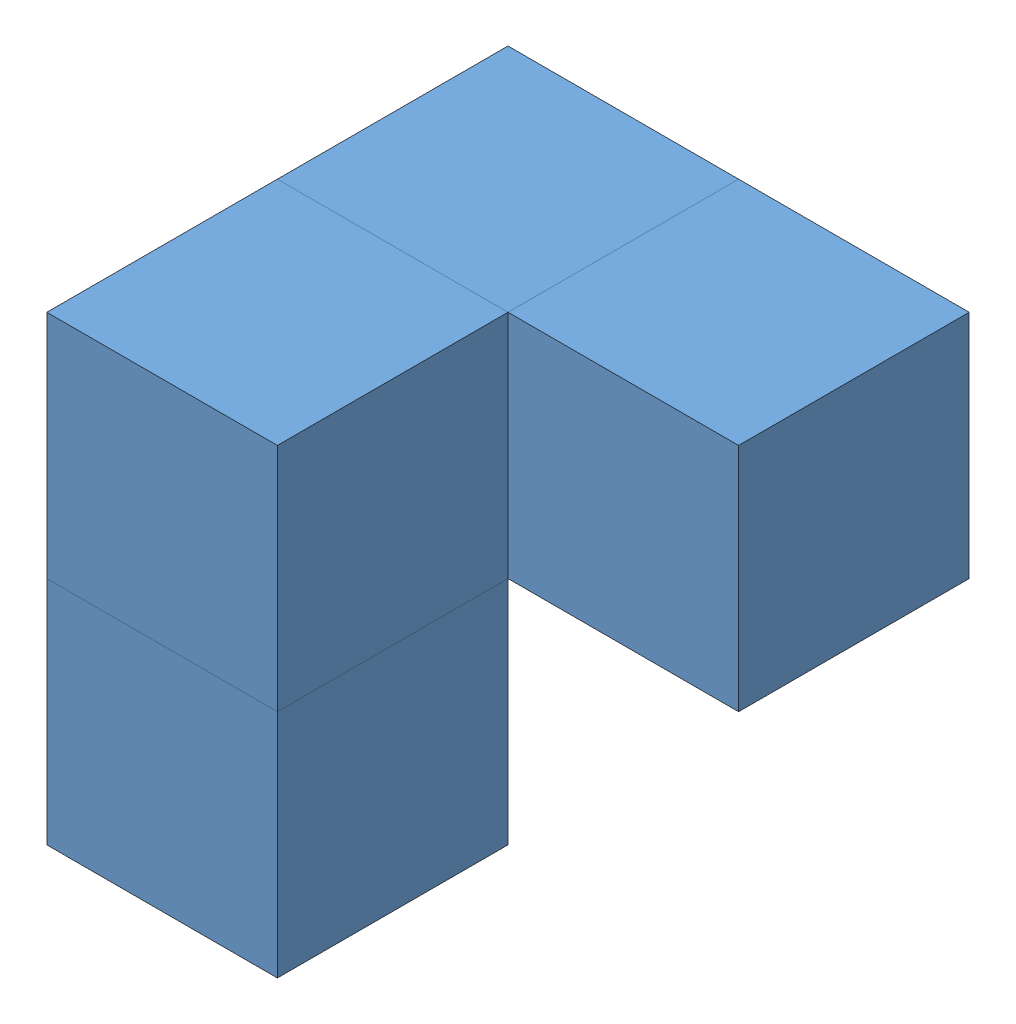
SolidWorks assembly Yellow Piece, configuration Default. Lengths in mm.
Overall size (40 40 40).
4 component instances, 1 part files, 9 mates.
Components (placement in the parent):
- cube-1: cube [Default] at origin size (20 20 20)
- cube-3: cube [Default] at (0 0 20) size (20 20 20)
- cube-4: cube [Default] at (20 0 0) size (20 20 20)
- cube-5: cube [Default] at (0 -20 20) size (20 20 20)
Mates (geometry in assembly coordinates):
- Coincident2: coincident anti-aligned: plane of cube-1 through (10 20 10) normal (1 0 0); plane of cube-4 through (10 20 10) normal (-1 0 0)
- Coincident3: coincident aligned: plane of cube-1 through (0 20 0) normal (0 1 0); plane of cube-4 through (20 20 0) normal (0 1 0)
- Coincident4: coincident anti-aligned: plane of cube-1 through (10 20 10) normal (0 0 1); plane of cube-3 through (10 20 10) normal (0 0 -1)
- Coincident5: coincident aligned: plane of cube-1 through (0 20 0) normal (0 1 0); plane of cube-3 through (0 20 20) normal (0 1 0)
- Coincident6: coincident aligned: plane of cube-1 through (10 20 10) normal (1 0 0); plane of cube-3 through (10 20 30) normal (1 0 0)
- Coincident7: coincident aligned: plane of cube-1 through (10 20 -10) normal (0 0 -1); plane of cube-4 through (30 20 -10) normal (0 0 -1)
- Coincident8: coincident anti-aligned: plane of cube-3 through (0 0 20) normal (0 -1 0); plane of cube-5 through (0 0 20) normal (0 1 0)
- Coincident9: coincident aligned: plane of cube-3 through (10 20 30) normal (0 0 1); plane of cube-5 through (10 0 30) normal (0 0 1)
- Coincident10: coincident aligned: plane of cube-3 through (-10 20 30) normal (-1 0 0); plane of cube-5 through (-10 0 30) normal (-1 0 0)
